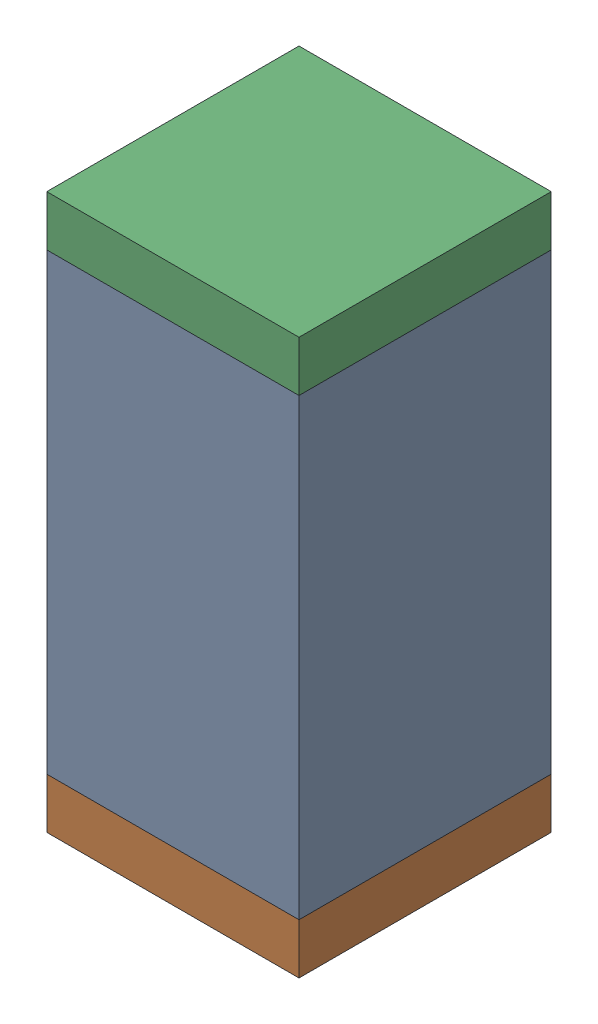
SolidWorks assembly C95, configuration Default. Lengths in mm.
Overall size (0.5 1.1 0.5).
6 component instances, 2 part files, 0 mates.
Components (placement in the parent):
- 791586336-1: 791586336 [Default] at (119.7 68.3 0) size (0.5 0.9 0.5)
  - Extruded_8-1: Extruded_8 [Default] at origin size (0.5 0.9 0.5)
- 810157360-1: 810157360 [Default] at (119.7 67.8 0) size (0.5 0.1 0.5)
  - Extruded_9-1: Extruded_9 [Default] at origin size (0.5 0.1 0.5)
- 810157360-2: 810157360 [Default] at (119.7 68.8 0) size (0.5 0.1 0.5)
  - Extruded_9-1: Extruded_9 [Default] at origin size (0.5 0.1 0.5)
